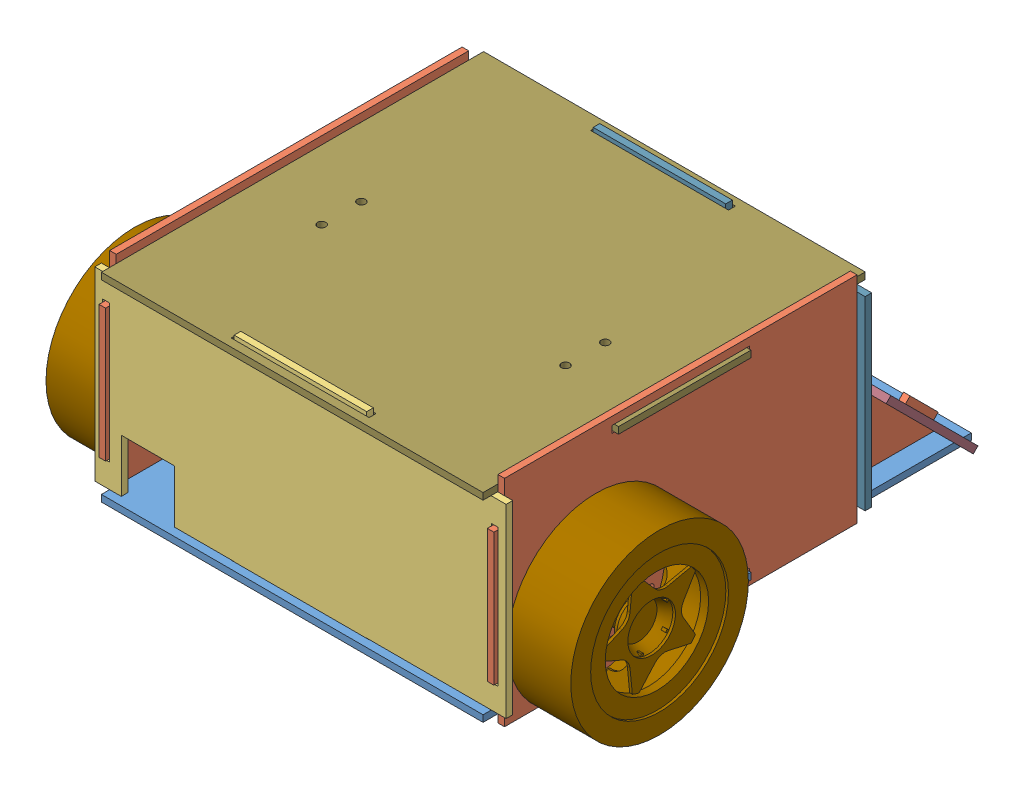
SolidWorks assembly prototype IR, configuration Default. Lengths in mm.
Overall size (198 88.65 184.2).
26 component instances, 15 part files, 80 mates.
Components (placement in the parent):
- bottom-1: bottom [Default] at (69.18 75.1651 107.655) size (152 2.5 184.2)
- side-1: side [Default] at (-5.32 112.7151 107.655) x (0 -1 0) z (0 0 1) size (81.2 2.5 167.64)
- back-1: back [Default] at (69.18 112.6651 176.655) x (0 1 0) z (-1 0 0) size (78 2.5 155.2)
- side-2: side [Default] at (141.18 112.7651 107.655) x (0 -1 0) z (0 0 1) size (81.2 2.5 167.64)
- battery holder-1: battery holder [Default] at (69.18 77.6651 100.655) size (75 20 41)
- breadboard-1: breadboard [Default] at (44.0497 77.6651 60.655) size (46 9 35)
- IR sensor-1: IR sensor [Default] at (100.1989 109.1651 148.5329) x (0 0 -1) z (-1 0 0) size (35.68 17.11 13.5)
- motor driver-1: motor driver [Default] at (69.18 77.6651 145.655) size (43 26.5 43)
- IR sensor-2: IR sensor [Default] at (38.161 109.1651 148.5329) x (0 0 -1) z (-1 0 0) size (35.68 17.11 13.5)
- IR sensor-3: IR sensor [Default] at (129.0784 109.1651 62.8071) x (0 0 1) z (1 0 0) size (35.68 17.11 13.5)
- IR sensor-4: IR sensor [Default] at (9.2816 109.1651 62.8071) x (0 0 1) z (1 0 0) size (35.68 17.11 13.5)
- motor-1: motor [Default] at (16.18 98.2151 132.655) x (0 0 1) z (-1 0 0) size (67.5 22 35)
- wheel-1: wheel [Default] at (-25.82 98.2151 140.155) x (0 -1 0) z (0 0 -1) size (67 27 67)
- black disk-1: black disk [Default] at (24.18 98.2151 140.155) x (0 1 0) z (0 0 1) size (26 3 26)
- encoder-1: encoder [Default] at (23.18 114.7151 131.155) x (0 0 -1) z (-1 0 0) size (35.68 12 13.5)
- top-2: top [Default] at (69.18 147.7651 107.655) size (152 2.5 144.2)
- wheel-2: wheel [Default] at (164.18 98.2651 140.155) x (0 1 0) z (0 0 -1) size (67 27 67)
- motor-2: motor [Default] at (122.18 98.2651 132.655) x (0 0 1) z (1 0 0) size (67.5 22 35)
- black disk-2: black disk [Default] at (114.18 98.2651 140.155) x (0 -1 0) z (0 0 1) size (26 3 26)
- encoder-3: encoder [Default] at (115.18 114.7651 131.155) x (0 0 -1) z (-1 0 0) size (35.68 12 13.5)
- defender-1: defender [Default] at (69.18 94.9618 19.3517) x (1 0 0) z (0 0.707107 0.707107) size (159.2 2.5 46.5)
- front-1: front [Default] at (69.13 112.7651 41.155) x (-1 0 0) z (0 -1 0) size (155.2 2.5 78)
- ultrasonic sensor-1: ultrasonic sensor [Default] at (69.13 125.5833 43.155) x (1 0 0) z (0 1 0) size (45 12 20)
- IR sensor-5: IR sensor [Default] at (111.63 114.0833 47.655) x (0 -1 0) z (1 0 0) size (35.68 17.11 13.5)
- IR sensor-6: IR sensor [Default] at (26.63 114.0833 47.655) x (0 -1 0) z (1 0 0) size (35.68 17.11 13.5)
- breadboard-2: breadboard [Default] at (92.8091 77.6651 60.655) size (46 9 35)
Mates (geometry in assembly coordinates):
- Coincident4: coincident anti-aligned: plane of bottom-1 through (141.18 77.6651 107.655) normal (1 0 0); plane of side-2 through (141.18 112.7651 107.655) normal (-1 0 0)
- Coincident5: coincident anti-aligned: plane of bottom-1 through (69.18 75.1651 107.655) normal (0 -1 0); plane of side-2 through (143.68 75.1651 133.655) normal (0 1 0)
- Width2: width anti-aligned: plane of bottom-1 through (69.18 77.6651 132.655) normal (0 0 1); plane of bottom-1 through (69.18 77.6651 82.655) normal (0 0 -1); plane of side-2 through (143.68 87.7651 41.155) normal (0 0 -1); plane of side-2 through (143.68 72.1651 174.155) normal (0 0 1)
- Coincident15: coincident anti-aligned: plane of bottom-1 through (69.18 77.6651 107.655) normal (0 1 0); plane of motor driver-1 through (69.18 77.6651 145.655) normal (0 -1 0)
- Concentric3: concentric aligned: circle of bottom-1; circle of IR sensor-1
- Parallel3: parallel aligned: line of bottom-1 through (141.18 77.6651 132.655) axis (0 0 1); line of IR sensor-1 through (106.9489 109.1651 133.0329) axis (0 0 1)
- Distance1: distance = 30 mm anti-aligned: plane of bottom-1 through (69.18 77.6651 107.655) normal (0 1 0); plane of IR sensor-1 through (100.1989 107.6651 148.5329) normal (0 -1 0)
- Concentric4: concentric anti-aligned: circle of bottom-1; circle of IR sensor-2
- Parallel4: parallel anti-aligned: line of bottom-1 through (-2.82 77.6651 132.655) axis (0 0 1); line of IR sensor-2 through (31.411 109.1651 164.0329) axis (0 0 -1)
- Distance2: distance = 30 mm anti-aligned: plane of bottom-1 through (69.18 77.6651 107.655) normal (0 1 0); plane of IR sensor-2 through (38.161 107.6651 148.5329) normal (0 -1 0)
- Concentric5: concentric aligned: circle of bottom-1; circle of IR sensor-3
- Parallel5: parallel aligned: line of bottom-1 through (141.18 77.6651 82.655) axis (0 0 -1); line of IR sensor-3 through (122.3284 109.1651 78.3071) axis (0 0 -1)
- Distance3: distance = 30 mm anti-aligned: plane of IR sensor-3 through (129.0784 107.6651 62.8071) normal (0 -1 0); plane of bottom-1 through (69.18 77.6651 107.655) normal (0 1 0)
- Parallel6: parallel aligned: line of bottom-1 through (-2.82 77.6651 82.655) axis (0 0 -1); line of IR sensor-4 through (2.5316 109.1651 78.3071) axis (0 0 -1)
- Concentric6: concentric anti-aligned: circle of bottom-1; circle of IR sensor-4
- Distance4: distance = 30 mm anti-aligned: plane of bottom-1 through (69.18 77.6651 107.655) normal (0 1 0); plane of IR sensor-4 through (9.2816 107.6651 62.8071) normal (0 -1 0)
- Concentric7: concentric aligned: circle of bottom-1; circle of battery holder-1
- Concentric8: concentric aligned: circle of bottom-1; circle of battery holder-1
- Coincident25: coincident anti-aligned: plane of bottom-1 through (69.18 77.6651 107.655) normal (0 1 0); plane of battery holder-1 through (69.18 77.6651 100.655) normal (0 -1 0)
- Coincident26: coincident anti-aligned: plane of bottom-1 through (69.18 77.6651 107.655) normal (0 1 0); plane of breadboard-1 through (44.0497 77.6651 60.655) normal (0 -1 0)
- Parallel7: parallel aligned: line of bottom-1 through (141.18 77.6651 82.655) axis (0 0 -1); line of breadboard-1 through (67.0497 86.6651 78.155) axis (0 0 -1)
- Coincident30: coincident anti-aligned: plane of motor-1 through (-2.82 92.2151 146.155) normal (-1 0 0); plane of wheel-1 through (-2.82 98.2151 140.155) normal (1 0 0)
- Concentric9: concentric anti-aligned: circle of motor-1; circle of wheel-1
- Coincident31: coincident anti-aligned: plane of side-1 through (-2.82 112.7151 107.655) normal (1 0 0); plane of motor-1 through (-2.82 92.2151 146.155) normal (-1 0 0)
- Coincident36: coincident aligned: plane of motor-1 through (24.18 98.2151 132.655) normal (1 0 0); plane of black disk-1 through (24.18 98.2151 140.155) normal (1 0 0)
- Concentric10: concentric aligned: circle of motor-1; circle of black disk-1
- Width7: width aligned: plane of back-1 through (94.18 77.6651 174.155) normal (1 0 0); plane of back-1 through (44.18 77.6651 174.155) normal (-1 0 0); plane of bottom-1 through (43.18 77.6651 107.655) normal (1 0 0); plane of bottom-1 through (95.18 77.6651 107.655) normal (-1 0 0)
- Coincident37: coincident anti-aligned: plane of bottom-1 through (69.18 77.6651 174.155) normal (0 0 1); plane of back-1 through (69.18 112.6651 174.155) normal (0 0 -1)
- Coincident38: coincident anti-aligned: plane of bottom-1 through (69.18 77.6651 107.655) normal (0 1 0); plane of back-1 through (146.78 77.6651 174.155) normal (0 -1 0)
- Parallel9: parallel anti-aligned: line of side-1 through (-2.82 153.3151 41.155) axis (0 0 1); line of encoder-1 through (16.43 114.7151 146.655) axis (0 0 -1)
- Tangent1: tangent anti-aligned: cylinder of black disk-1 through (22.18 98.2151 140.155) axis (1 0 0) radius 13; plane of encoder-1 through (23.18 111.2151 131.155) normal (0 -1 0)
- Width8: width aligned: plane of black disk-1 through (24.18 98.2151 140.155) normal (1 0 0); plane of black disk-1 through (22.18 98.2151 140.155) normal (-1 0 0); plane of encoder-1 through (29.43 102.7151 131.155) normal (1 0 0); plane of encoder-1 through (16.93 102.7151 131.155) normal (-1 0 0)
- Parallel10: parallel anti-aligned: line of motor-1 through (24.18 100.4651 139.0653) axis (0 -1 0); line of black disk-1 through (24.18 95.9651 138.5738) axis (0 1 0)
- Width9: width anti-aligned: plane of encoder-1 through (23.18 102.7151 145.655) normal (0 0 1); plane of encoder-1 through (23.18 102.7151 134.655) normal (0 0 -1); plane of motor-1 through (24.18 98.2151 139.0653) normal (0 0 -1); plane of motor-1 through (24.18 98.2151 141.2447) normal (0 0 1)
- Parallel13: parallel aligned: line of motor-1 through (24.18 100.4651 141.2447) axis (0 -1 0); line of wheel-1 through (-2.82 100.4512 142.155) axis (0 -1 0)
- Concentric14: concentric aligned: circle of side-1; circle of wheel-1
- Concentric15: concentric aligned: circle of side-1; circle of motor-1
- Concentric16: concentric aligned: circle of side-1; circle of motor-1
- Coincident44: coincident anti-aligned: plane of bottom-1 through (-2.82 77.6651 107.655) normal (-1 0 0); plane of side-1 through (-2.82 112.7151 107.655) normal (1 0 0)
- Width10: width aligned: plane of bottom-1 through (69.18 77.6651 82.655) normal (0 0 -1); plane of side-1 through (69.18 77.6651 132.655) normal (0 0 1); plane of bottom-1 through (-2.82 137.7151 37.155) normal (0 0 -1); plane of side-1 through (-2.82 137.7151 178.155) normal (0 0 1)
- Width11: width anti-aligned: plane of side-1 through (-2.82 77.7151 133.655) normal (0 -1 0); plane of bottom-1 through (-2.82 75.1151 133.655) normal (0 1 0); plane of side-1 through (69.18 77.6651 107.655) normal (0 1 0); plane of bottom-1 through (69.18 75.1651 107.655) normal (0 -1 0)
- Width13: width anti-aligned: plane of top-2 through (69.18 150.2651 107.655) normal (0 1 0); plane of side-1 through (69.18 147.7651 107.655) normal (0 -1 0); plane of top-2 through (-2.82 150.3151 133.655) normal (0 -1 0); plane of side-1 through (-2.82 147.7151 133.655) normal (0 1 0)
- Width14: width aligned: plane of side-1 through (-2.82 150.3151 133.655) normal (0 0 -1); plane of top-2 through (-2.82 150.3151 81.655) normal (0 0 1); plane of side-1 through (-2.82 150.2651 82.655) normal (0 0 -1); plane of top-2 through (-6.82 150.2651 132.655) normal (0 0 1)
- Width15: width anti-aligned: plane of top-2 through (-2.82 150.2651 132.655) normal (-1 0 0); plane of back-1 through (141.18 150.2651 179.755) normal (1 0 0); plane of top-2 through (94.18 147.6651 174.155) normal (1 0 0); plane of back-1 through (44.18 147.6651 174.155) normal (-1 0 0)
- Concentric17: concentric anti-aligned: circle of wheel-2; circle of motor-2
- Coincident47: coincident anti-aligned: plane of wheel-2 through (141.18 98.2651 140.155) normal (-1 0 0); plane of motor-2 through (141.18 104.2651 146.155) normal (1 0 0)
- Parallel14: parallel anti-aligned: line of motor-2 through (114.18 96.0151 139.0653) axis (0 1 0); line of black disk-2 through (114.18 100.5151 138.5738) axis (0 -1 0)
- Concentric18: concentric aligned: circle of motor-2; circle of black disk-2
- Coincident48: coincident aligned: plane of motor-2 through (114.18 98.2651 132.655) normal (-1 0 0); plane of black disk-2 through (114.18 98.2651 140.155) normal (-1 0 0)
- Parallel15: parallel aligned: line of wheel-2 through (141.18 96.029 142.155) axis (0 1 0); line of motor-2 through (114.18 96.0151 141.2447) axis (0 1 0)
- Concentric19: concentric anti-aligned: circle of side-2; circle of wheel-2
- Coincident50: coincident anti-aligned: plane of side-2 through (141.18 112.7651 107.655) normal (-1 0 0); plane of motor-2 through (141.18 104.2651 146.155) normal (1 0 0)
- Parallel16: parallel aligned: line of side-2 through (141.18 153.3651 41.155) axis (0 0 1); line of motor-2 through (122.18 109.2651 114.155) axis (0 0 1)
- Width18: width aligned: plane of encoder-3 through (108.93 102.7651 131.155) normal (-1 0 0); plane of black disk-2 through (121.43 102.7651 131.155) normal (1 0 0); plane of encoder-3 through (114.18 98.2651 140.155) normal (-1 0 0); plane of black disk-2 through (116.18 98.2651 140.155) normal (1 0 0)
- Tangent3: tangent anti-aligned: cylinder of black disk-2 through (116.18 98.2651 140.155) axis (-1 0 0) radius 13; plane of encoder-3 through (115.18 111.2651 131.155) normal (0 -1 0)
- Width19: width aligned: plane of encoder-3 through (115.18 102.7651 134.655) normal (0 0 -1); plane of motor-2 through (115.18 102.7651 145.655) normal (0 0 1); plane of encoder-3 through (114.18 98.2651 139.0653) normal (0 0 -1); plane of motor-2 through (114.18 98.2651 141.2447) normal (0 0 1)
- Concentric20: concentric anti-aligned: circle of side-2; circle of motor-2
- Concentric21: concentric anti-aligned: circle of side-2; circle of motor-2
- Coincident52: coincident anti-aligned: plane of side-2 through (141.18 148.0151 72.405) normal (0 0.707107 -0.707107); plane of defender-1 through (69.18 94.9618 19.3517) normal (0 -0.707107 0.707107)
- Width20: width anti-aligned: plane of side-2 through (141.18 54.4085 49.2984) normal (0 -0.707107 -0.707107); plane of defender-1 through (141.18 65.0151 59.905) normal (0 0.707107 0.707107); plane of side-2 through (143.78 91.0727 11.9271) normal (0 0.707107 0.707107); plane of defender-1 through (143.78 102.3864 23.2408) normal (0 -0.707107 -0.707107)
- Coincident53: coincident anti-aligned: plane of side-2 through (141.18 112.7651 107.655) normal (-1 0 0); plane of defender-1 through (141.18 102.3864 23.2408) normal (1 0 0)
- Coincident54: coincident anti-aligned: plane of side-1 through (-2.82 112.7151 107.655) normal (1 0 0); plane of defender-1 through (-2.82 102.3864 23.2408) normal (-1 0 0)
- Coincident55: coincident anti-aligned: plane of side-2 through (143.68 137.7651 41.155) normal (0 0 -1); plane of front-1 through (69.13 112.7651 41.155) normal (0 0 1)
- Coincident56: coincident anti-aligned: plane of top-2 through (69.18 147.7651 107.655) normal (0 -1 0); plane of front-1 through (94.13 147.7651 38.655) normal (0 1 0)
- Width23: width aligned: plane of side-2 through (143.68 112.7651 107.655) normal (1 0 0); plane of front-1 through (141.18 112.7651 107.655) normal (-1 0 0); plane of side-2 through (141.13 86.7651 38.655) normal (1 0 0); plane of front-1 through (143.73 86.7651 38.655) normal (-1 0 0)
- Coincident57: coincident anti-aligned: plane of front-1 through (69.13 112.7651 41.155) normal (0 0 1); plane of ultrasonic sensor-1 through (69.13 125.5833 41.155) normal (0 0 -1)
- Concentric22: concentric aligned: circle of front-1; circle of ultrasonic sensor-1
- Concentric23: concentric aligned: circle of front-1; circle of IR sensor-5
- Distance5: distance = 5 mm anti-aligned: plane of front-1 through (69.13 112.7651 41.155) normal (0 0 1); plane of IR sensor-5 through (111.63 114.0833 46.155) normal (0 0 -1)
- Parallel17: parallel aligned: line of front-1 through (119.13 133.0833 41.155) axis (0 -1 0); line of IR sensor-5 through (118.38 129.5833 47.655) axis (0 -1 0)
- Concentric24: concentric aligned: circle of front-1; circle of IR sensor-6
- Parallel18: parallel aligned: line of front-1 through (34.13 133.0833 41.155) axis (0 -1 0); line of IR sensor-6 through (33.38 129.5833 47.655) axis (0 -1 0)
- Distance6: distance = 5 mm anti-aligned: plane of front-1 through (69.13 112.7651 41.155) normal (0 0 1); plane of IR sensor-6 through (26.63 114.0833 46.155) normal (0 0 -1)
- Width24: width anti-aligned: plane of battery holder-1 through (31.68 97.6651 80.155) normal (0 0 -1); plane of front-1 through (69.13 112.7651 41.155) normal (0 0 1); plane of breadboard-1 through (21.0497 86.6651 78.155) normal (0 0 1); plane of breadboard-1 through (21.0497 86.6651 43.155) normal (0 0 -1)
- Coincident62: coincident anti-aligned: plane of bottom-1 through (69.18 77.6651 107.655) normal (0 1 0); plane of breadboard-2 through (92.8091 77.6651 60.655) normal (0 -1 0)
- Width25: width aligned: plane of battery holder-1 through (31.68 97.6651 80.155) normal (0 0 -1); plane of front-1 through (69.13 112.7651 41.155) normal (0 0 1); plane of breadboard-2 through (69.8091 86.6651 43.155) normal (0 0 -1); plane of breadboard-2 through (69.8091 86.6651 78.155) normal (0 0 1)
- Lock1: lock: unknown of bottom-1; unknown of breadboard-1
- Lock2: lock: unknown of bottom-1; unknown of breadboard-2
- Concentric25: concentric aligned: circle of bottom-1; circle of motor driver-1
- Concentric26: concentric aligned: circle of bottom-1; circle of motor driver-1
